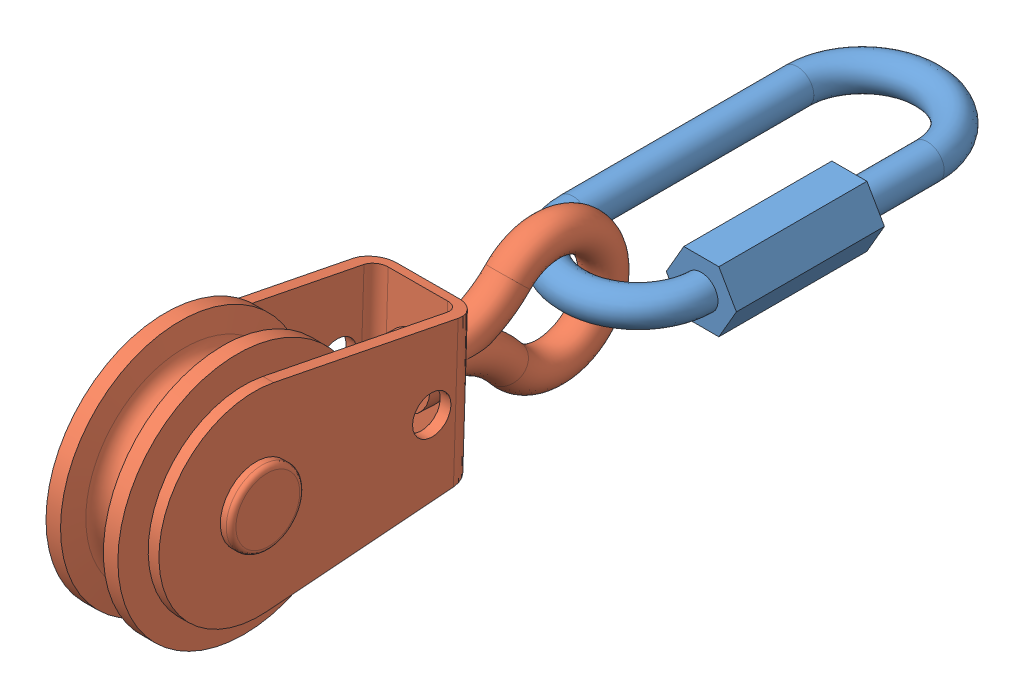
SolidWorks assembly Pulley_and_chainlink_subassembly, configuration Default. Lengths in mm.
Overall size (23.84 35.39 112.3).
2 component instances, 2 part files, 0 mates.
Components (placement in the parent):
- chainlink1-1: chainlink1 [Default] at (18.2193 25.8525 53.8788) size (23.84 7.95 50.8)
- 3213T57_Pulley-1: 3213T57_Pulley [3213T57] at (16.9878 27.9637 109.3807) x (0.014814 -0.99874 0.047954) z (0.999811 0.0154 0.01188) size (31.75 71.72 16.59)
